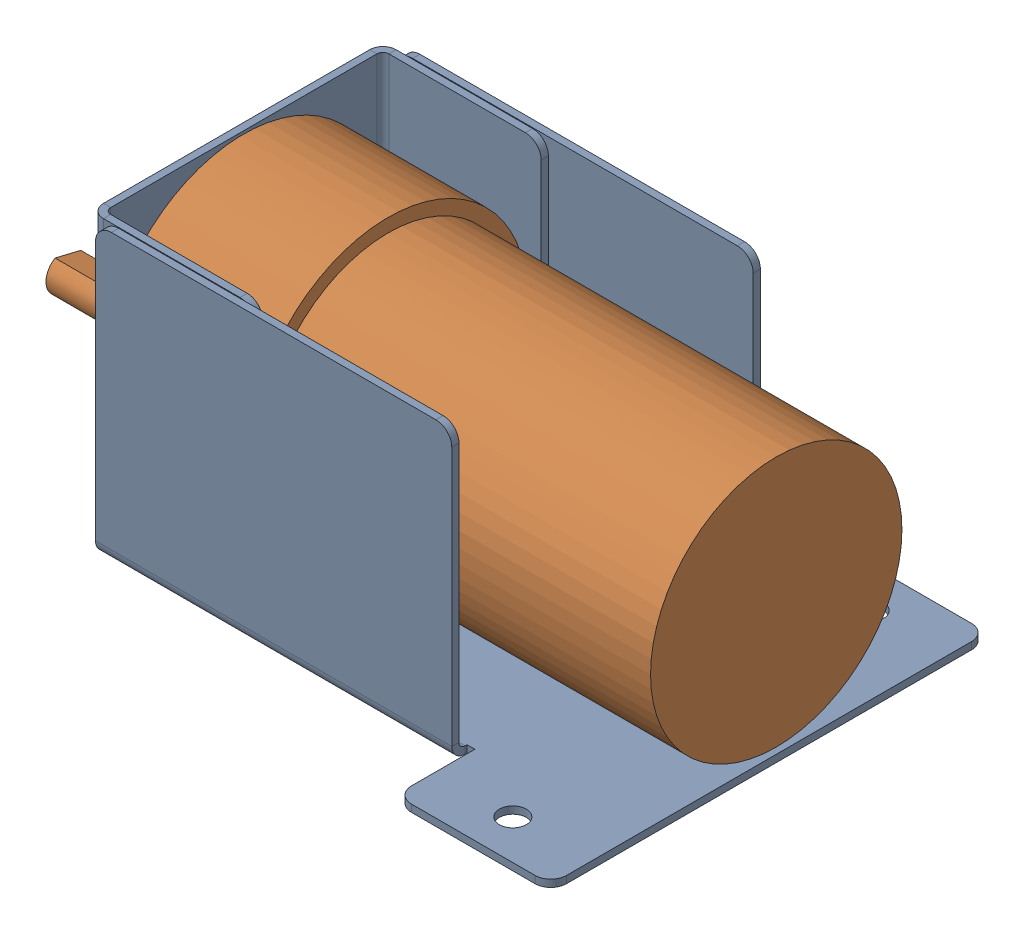
SolidWorks assembly MirrorBarbCole Motor with Fixture1, configuration Default. Lengths in mm.
Overall size (89.87 36.41 55.14).
2 component instances, 2 part files, 2 mates.
Components (placement in the parent):
- MirrorBarbCole Geared Fixture1-1: MirrorBarbCole Geared Fixture1 [Default] at (-41.6291 -27.9181 -27.027) size (67.26 36.41 55.14)
- MirrorMotor BarbCole Geared1-1: MirrorMotor BarbCole Geared1 [Default] at (-22.4819 -10.3495 -9.4562) size (89.87 35.14 35.14)
Mates (geometry in assembly coordinates):
- Concentric1: concentric aligned: circle of MirrorBarbCole Geared Fixture1-1; circle of MirrorMotor BarbCole Geared1-1
- Coincident1: coincident anti-aligned: plane of MirrorBarbCole Geared Fixture1-1 through (-40.7191 -27.9181 -27.027) normal (1 0 0); plane of MirrorMotor BarbCole Geared1-1 through (-40.7191 -10.3495 -9.4562) normal (-1 0 0)
